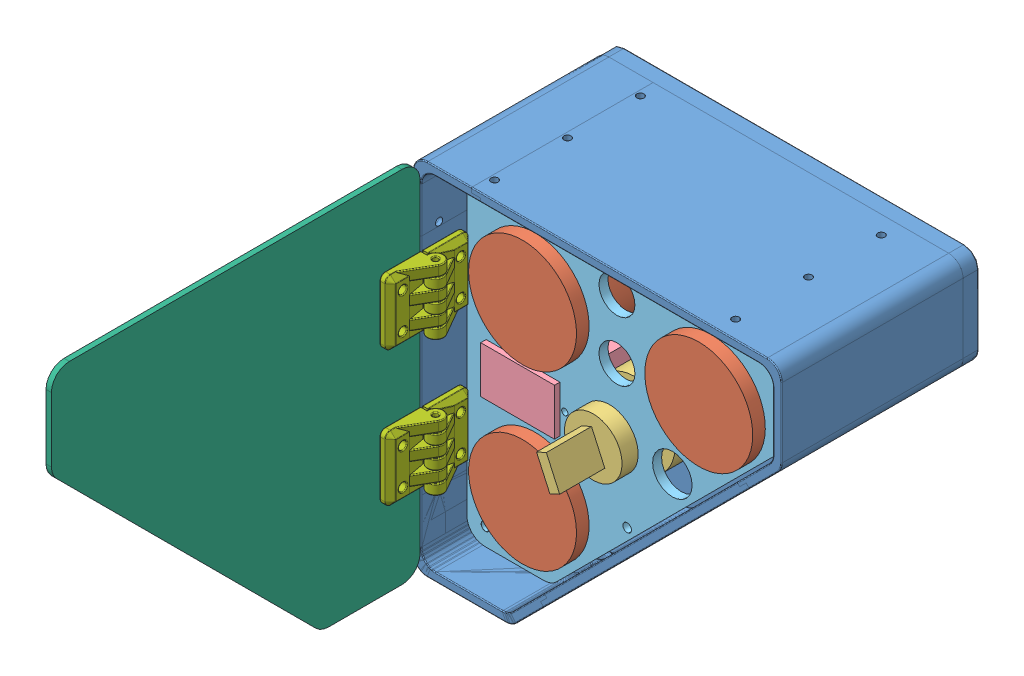
SolidWorks assembly prova5, configuration Default. Lengths in mm.
Overall size (255.51 233.29 315.2).
12 component instances, 7 part files, 22 mates.
Components (placement in the parent):
- base prova-1: base prova [Default] at (7.6456 -113.0863 -73.1) size (255.51 233.29 109.6)
- tachi-2: tachi [Default] at (148.2456 27.3137 -23.9) x (0.966989 0.254818 0) z (0.254818 -0.966989 0) size (60 42 60)
- tachi-3: tachi [Default] at (50.2456 27.3137 -23.9) x (0.976184 0.216942 0) z (0.216942 -0.976184 0) size (60 42 60)
- tachi-4: tachi [Default] at (50.2456 -68.6863 -23.9) x (0.916703 0.399569 0) z (0.399569 -0.916703 0) size (60 42 60)
- chiave-1: chiave [Default] at (91.5651 -20.6863 -38.7) x (-0.411199 0.911545 0) z (0.911545 0.411199 0) size (45 83.9 45)
- scree-1: scree [Default] at (43.4956 -20.6863 -50.9) x (1 0 0) z (0 -1 0) size (41 65 26)
- layer2.2-1: layer2.2 [Default] at (12.2456 -107.6863 6.1) size (195 190 5)
- lid prova-1: lid prova [Default] at (12.2456 -113.0863 37.1) x (0 0 1) z (-1 0 0) size (205 200 3)
- hinge-1: hinge [Default] at (16.2456 -68.4863 51.5) x (0 0 -1) z (0 -1 0) size (27.6 12.5 36)
- hinge-2: hinge [Default] at (16.2456 -32.4863 21.5) x (0 0 1) z (0 1 0) size (27.6 12.5 36)
- hinge-3: hinge [Default] at (16.2456 42.5137 21.5) x (0 0 1) z (0 1 0) size (27.6 12.5 36)
- hinge-4: hinge [Default] at (16.2456 6.5137 51.5) x (0 0 -1) z (0 -1 0) size (27.6 12.5 36)
Mates (geometry in assembly coordinates):
- Coincidente11: coincident anti-aligned: plane of base prova-1 through (57.4265 -100.4863 6.1) normal (0 0 1); plane of layer2.2-1 through (22.2456 72.3137 6.1) normal (0 0 -1)
- Coincidente12: coincident anti-aligned: plane of base prova-1 through (12.2456 74.3137 -64.5) normal (1 0 0); plane of layer2.2-1 through (12.2456 -97.6863 11.1) normal (-1 0 0)
- Coincidente13: coincident anti-aligned: plane of base prova-1 through (200.0456 82.3137 -64.5) normal (0 -1 0); plane of layer2.2-1 through (22.2456 82.3137 11.1) normal (0 1 0)
- Concentrico6: concentric aligned: circle of tachi-2; circle of layer2.2-1
- Coincidente14: coincident aligned: circle of tachi-2; plane of layer2.2-1 through (22.2456 72.3137 11.1) normal (0 0 1)
- Concentrico7: concentric anti-aligned: circle of tachi-3; circle of layer2.2-1
- Coincidente15: coincident aligned: circle of tachi-3; plane of layer2.2-1 through (22.2456 72.3137 11.1) normal (0 0 1)
- Concentrico8: concentric aligned: circle of tachi-4; circle of layer2.2-1
- Coincidente16: coincident aligned: circle of tachi-4; plane of layer2.2-1 through (22.2456 72.3137 11.1) normal (0 0 1)
- Concentrico9: concentric aligned: circle of chiave-1; circle of layer2.2-1
- Coincidente17: coincident aligned: circle of chiave-1; plane of layer2.2-1 through (22.2456 72.3137 11.1) normal (0 0 1)
- Coincidente18: coincident anti-aligned: plane of scree-1 through (62.9956 -8.6863 11.1) normal (1 0 0); plane of layer2.2-1 through (62.9956 -8.6863 4.1) normal (-1 0 0)
- Coincidente19: coincident anti-aligned: plane of scree-1 through (23.9956 -8.6863 11.1) normal (0 1 0); plane of layer2.2-1 through (25.9956 -8.6863 4.1) normal (0 -1 0)
- Coincidente20: coincident: line of scree-1 through (22.9956 -7.6863 11.1) axis (0 -1 0); plane of layer2.2-1 through (22.2456 72.3137 11.1) normal (0 0 1)
- Coincidente21: coincident anti-aligned: plane of lid prova-1 through (12.2456 -103.0863 87.9579) normal (1 0 0); plane of hinge-4 through (12.2456 42.5137 59.6) normal (-1 0 0)
- Coincidente22: coincident aligned: plane of base prova-1 through (62.6456 -113.0863 36.5) normal (0 -1 0); plane of lid prova-1 through (9.2456 -113.0863 87.9579) normal (0 -1 0)
- AngoloLimite1: limit planar angle = 3.141593 rad anti-aligned: plane of lid prova-1 through (9.2456 -103.0863 87.9579) normal (-1 0 0); plane of base prova-1 through (7.6456 -113.0863 36.5) normal (-1 0 0)
- Coincidente23: coincident anti-aligned: plane of lid prova-1 through (12.2456 -103.0863 87.9579) normal (1 0 0); plane of hinge-1 through (12.2456 -32.4863 59.6) normal (-1 0 0)
- Coincidente24: coincident: plane of base prova-1 through (7.6456 -113.0863 36.5) normal (0 0 1); line of hinge-1 through (20.2456 -16.1773 36.5) axis (0 -1 0)
- Coincidente25: coincident anti-aligned: plane of base prova-1 through (12.2456 74.3137 -64.5) normal (1 0 0); plane of hinge-2 through (12.2456 -68.4863 13.4) normal (-1 0 0)
- Distanza1: distance = 40 mm anti-aligned: plane of base prova-1 through (20.2456 -108.4863 -64.5) normal (0 1 0); plane of hinge-2 through (20.2456 -68.4863 36.5) normal (0 -1 0)
- Coincidente27: coincident: line of lid prova-1 through (12.2456 76.9137 37.1) axis (0 -1 0); line of hinge-4 through (12.2456 42.5137 37.1) axis (0 -1 0)
